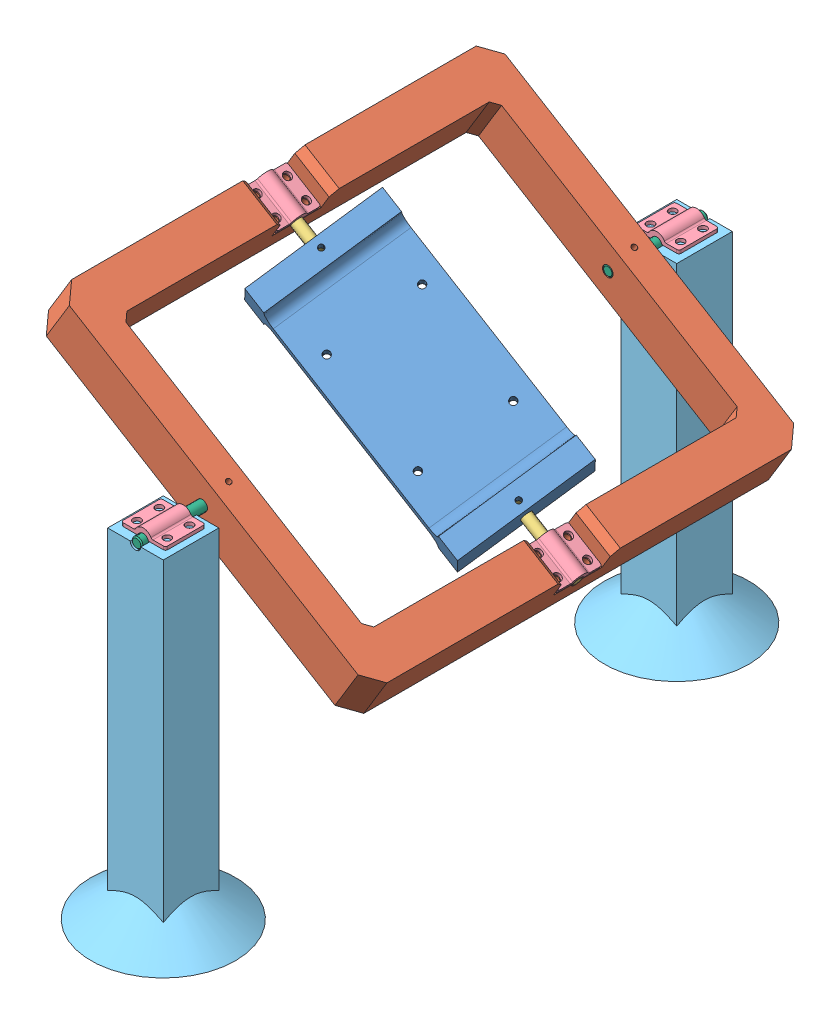
SolidWorks assembly Calibration Device, configuration Default. Lengths in mm.
Overall size (152.24 204.06 296).
12 component instances, 6 part files, 25 mates.
Components (placement in the parent):
- Mounting Plate-1: Mounting Plate [Default] x (0.854529 -0.519404 0) z (-0.239067 -0.393315 0.887779) size (112 15 55)
- Loop-1: Loop [Default] x (0.854529 -0.519404 0) z (0 0 1) size (166 20 196)
- Shaft1-1: Shaft1 [Default] at (-55.9716 34.021 0) x (0.239067 0.393315 -0.887779) z (0.854529 -0.519404 0) size (4.76 4.76 35)
- Shaft1-2: Shaft1 [Default] at (55.9716 -34.021 0) x (-0.239067 -0.393315 0.887779) z (-0.854529 0.519404 0) size (4.76 4.76 35)
- Clamp-5: Clamp [Default] at (-62.9754 38.8632 0) x (0 0 -1) z (0.854529 -0.519404 0) size (20 4 18)
- Clamp-6: Clamp [Default] at (63.4948 -38.0086 0) x (0 0 1) z (-0.854529 0.519404 0) size (20 4 18)
- Pillars-3: Pillars [Default] at (0 0 115.5) size (65 152.4 65)
- Clamp-7: Clamp [Default] at (0 0.5 115.5) size (20 4 18)
- Pillars-4: Pillars [Default] at (0 0 -115.5) size (65 152.4 65)
- Clamp-8: Clamp [Default] at (0 0.5 -115.5) size (20 4 18)
- Shaft2-1: Shaft2 [Default] at (0 0 84.5) x (-0.854529 0.519404 0) z (0 0 -1) size (4.76 4.76 43)
- Shaft2-2: Shaft2 [Default] at (0 0 -84.5) x (0.854529 -0.519404 0) z (0 0 1) size (4.76 4.76 43)
Mates (geometry in assembly coordinates):
- Concentric2: concentric: circle of Mounting Plate-1; circle of Loop-1
- Distance1: distance = 9 mm: plane of Loop-1 through (60.7384 -25.216 -80) normal (-0.854529 0.519404 0); plane of Mounting Plate-1 through (47.8536 -29.0866 0) normal (0.854529 -0.519404 0)
- Concentric3: concentric: cylinder of Mounting Plate-1 through (-41.0174 24.9314 0) axis (-0.854529 0.519404 0) radius 2.3813; cylinder of Shaft1-1 through (-41.0174 24.9314 0) axis (-0.854529 0.519404 0) radius 2.3813
- Concentric4: concentric: cylinder of Mounting Plate-1 through (-47.8943 21.3185 -3.4525) axis (0.461116 0.758632 0.460271) radius 1.1906; cylinder of Shaft1-1 through (-45.5335 25.2025 -1.096) axis (0.461116 0.758632 0.460271) radius 1.1906
- Concentric6: concentric: cylinder of Mounting Plate-1 through (41.0174 -24.9314 0) axis (0.854529 -0.519404 0) radius 2.3813; cylinder of Shaft1-2 through (41.0174 -24.9314 0) axis (0.854529 -0.519404 0) radius 2.3813
- Concentric7: concentric: cylinder of Mounting Plate-1 through (40.9767 -32.6995 -3.4525) axis (0.461116 0.758632 0.460271) radius 1.1906; cylinder of Shaft1-2 through (43.3375 -28.8155 -1.096) axis (0.461116 0.758632 0.460271) radius 1.1906
- Concentric18: concentric: cylinder of Loop-1 through (-64.157 27.2927 -6.8) axis (0.519404 0.854529 0) radius 1.75; cylinder of Clamp-5 through (-58.7033 36.2653 -6.8) axis (0.519404 0.854529 0) radius 1.75
- Concentric19: concentric: cylinder of Loop-1 through (-72.7023 32.4868 6.8) axis (0.519404 0.854529 0) radius 1.75; cylinder of Clamp-5 through (-67.2486 41.4593 6.8) axis (0.519404 0.854529 0) radius 1.75
- Concentric20: concentric: cylinder of Shaft1-1 through (-41.0174 24.9314 0) axis (-0.854529 0.519404 0) radius 2.3813; cylinder of Clamp-5 through (-70.9267 43.1111 0) axis (0.854529 -0.519404 0) radius 2.3813
- Concentric21: concentric: cylinder of Loop-1 through (53.7679 -44.385 6.8) axis (0.519404 0.854529 0) radius 1.75; cylinder of Clamp-6 through (59.2217 -35.4125 6.8) axis (0.519404 0.854529 0) radius 1.75
- Concentric22: concentric: cylinder of Loop-1 through (62.3132 -49.5791 -6.8) axis (0.519404 0.854529 0) radius 1.75; cylinder of Clamp-6 through (67.767 -40.6065 -6.8) axis (0.519404 0.854529 0) radius 1.75
- Coincident3: coincident: cylinder of Shaft1-2 through (41.0174 -24.9314 0) axis (0.854529 -0.519404 0) radius 2.3813; circle of Clamp-6
- Concentric25: concentric: circle of Pillars-3; circle of Clamp-7
- Concentric28: concentric: cylinder of Pillars-4 through (0 0 -148.001) axis (0 0 1) radius 2.3813; circle of Clamp-8
- Concentric29: concentric: cylinder of Loop-1 through (0 0 -98) axis (0 0 1) radius 2.3813; cylinder of Pillars-3 through (0 0 82.999) axis (0 0 1) radius 2.3813
- Distance2: distance = 5 mm: plane of Pillars-3 through (-12.5 -152.4 103) normal (0 0 -1); plane of Loop-1 through (-65.7318 51.6558 98) normal (0 0 1)
- Concentric30: concentric: cylinder of Loop-1 through (0 0 -98) axis (0 0 1) radius 2.3813; cylinder of Pillars-4 through (0 0 -148.001) axis (0 0 1) radius 2.3813
- Distance3: distance = 5 mm: plane of Loop-1 through (-65.7318 51.6558 -98) normal (0 0 -1); plane of Pillars-4 through (-12.5 -152.4 -103) normal (0 0 1)
- Coincident10: coincident: plane of Pillars-3 through (0 -152.4 115.5) normal (0 -1 0); plane of Pillars-4 through (0 -152.4 -115.5) normal (0 -1 0)
- Concentric31: concentric: cylinder of Pillars-3 through (6.8 0 110.5) axis (0 1 0) radius 1.25; cylinder of Clamp-7 through (6.8 0.499 110.5) axis (0 1 0) radius 1.75
- Concentric32: concentric: cylinder of Pillars-4 through (6.8 0 -120.5) axis (0 1 0) radius 1.25; cylinder of Clamp-8 through (6.8 0.499 -120.5) axis (0 1 0) radius 1.75
- Concentric33: concentric: cylinder of Loop-1 through (-5.1946 -8.5461 91.25) axis (0.519404 0.854529 0) radius 1.1906; cylinder of Shaft2-1 through (-1.2368 -2.0348 91.25) axis (0.519404 0.854529 0) radius 1.1906
- Coincident11: coincident: circle of Loop-1; cylinder of Shaft2-1 through (0 0 127.5) axis (0 0 -1) radius 2.3813
- Concentric34: concentric: cylinder of Loop-1 through (-5.1946 -8.5461 -91.25) axis (0.519404 0.854529 0) radius 1.1906; cylinder of Shaft2-2 through (-1.2368 -2.0348 -91.25) axis (0.519404 0.854529 0) radius 1.1906
- Concentric35: concentric: cylinder of Loop-1 through (0 0 -98) axis (0 0 1) radius 2.3813; cylinder of Shaft2-2 through (0 0 -127.5) axis (0 0 1) radius 2.3813
